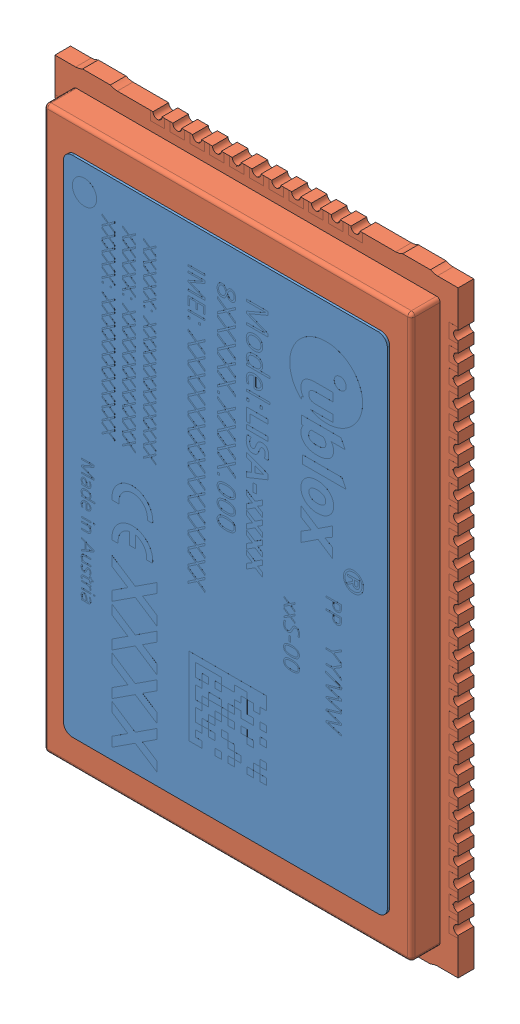
SolidWorks assembly LISA, configuration Default. Lengths in mm.
Overall size (22.4 33.4 2.6).
2 component instances, 2 part files, 0 mates.
Components (placement in the parent):
- Lisa Product Label-1: Lisa Product Label [Default] at (-12.091 14.0215 1.6) x (0 -1 0) z (0 0 1) size (28 18 0.13)
- Lisa-1: Lisa [Default] at (-14.291 -16.5785 0) size (22.4 33.4 2.47)
